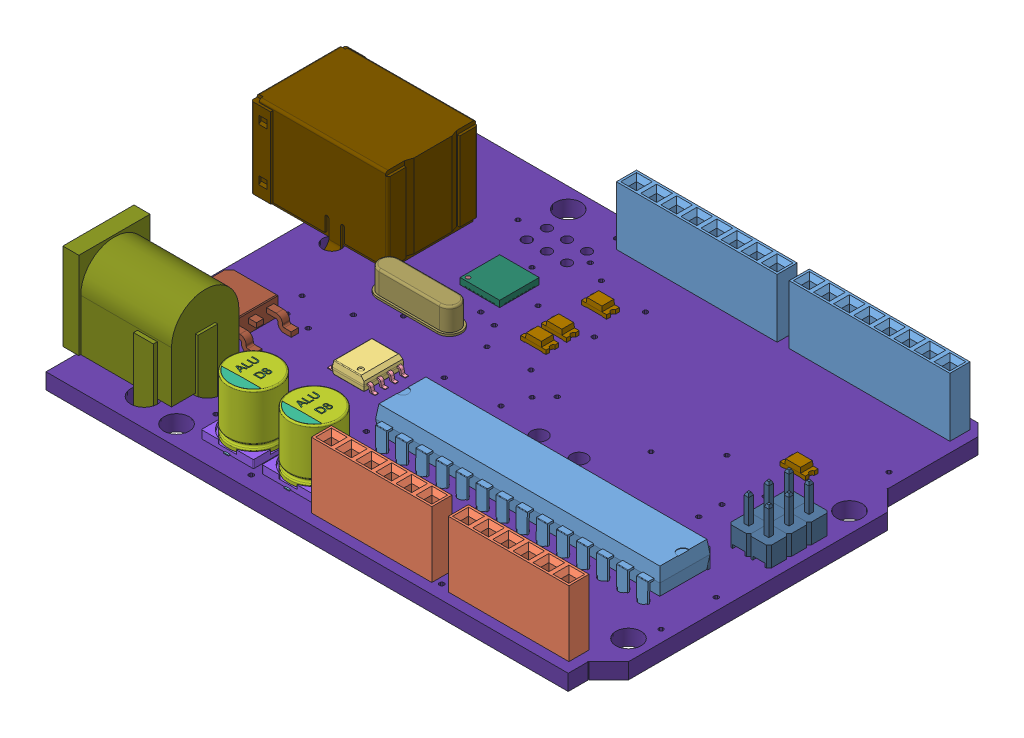
SolidWorks assembly ArduinoUno, configuration Predeterminado. Lengths in mm.
Overall size (75.71 19 55.26).
37 component instances, 20 part files, 8 mates.
Components (placement in the parent):
- Final-1: Final [Predeterminado] at (-36.0382 -5.851 101.423) size (74.75 15.48 53.34)
  - Stackable Female Pin Header_Default-1: Stackable Female Pin Header_Default [Predeterminado] at (23.9415 1.1201 -50.7298) size (20.32 8.3 2.54)
  - Stackable Female Pin Header_6 Way-1: Stackable Female Pin Header_6 Way [Predeterminado] at (33.5006 2 -2.5872) size (15.24 8.3 2.54)
  - User Library-SOIC-8_Default-1: User Library-SOIC-8_Default [Predeterminado] at (20.4108 1.85 -20.3024) x (0 0 -1) z (1 0 0) size (5 1.75 6.01)
    - User Library-SOIC-8_SOIC-8_Body_1_Default-1: User Library-SOIC-8_SOIC-8_Body_1_Default [Predeterminado] at origin size (5 1.6 4)
    - User Library-SOIC-8_SOIC-8_Pins_1_Default-1: User Library-SOIC-8_SOIC-8_Pins_1_Default [Predeterminado] at origin size (4.23 0.99 6.01)
  - User Library-ALU-D8_Default-1: User Library-ALU-D8_Default [Predeterminado] at (28.1214 1.8 -5.7935) x (0 0 -1) z (0 1 0) size (7 6.6 7.7)
    - User Library-ALU-D8_Pins_1_Default-1: User Library-ALU-D8_Pins_1_Default [Predeterminado] at origin size (7 0.65 0.4)
    - User Library-ALU-D8_Beschriftung_1_Default-1: User Library-ALU-D8_Beschriftung_1_Default [Predeterminado] at origin size (4.35 4.98 0.11)
    - User Library-ALU-D8_K_X_F6rper_1_Default-1: User Library-ALU-D8_K_X_F6rper_1_Default [Predeterminado] at origin size (6.3 6.3 7)
    - User Library-ALU-D8_Fuss_1_Default-1: User Library-ALU-D8_Fuss_1_Default [Predeterminado] at origin size (6.6 6.6 1)
  - User Library-ALU-D8_Default-2: User Library-ALU-D8_Default [Predeterminado] at (20.4464 1.8 -5.7935) x (0 0 -1) z (0 1 0) size (7 6.6 7.7)
    - User Library-ALU-D8_Pins_1_Default-1: User Library-ALU-D8_Pins_1_Default [Predeterminado] at origin size (7 0.65 0.4)
    - User Library-ALU-D8_Beschriftung_1_Default-1: User Library-ALU-D8_Beschriftung_1_Default [Predeterminado] at origin size (4.35 4.98 0.11)
    - User Library-ALU-D8_K_X_F6rper_1_Default-1: User Library-ALU-D8_K_X_F6rper_1_Default [Predeterminado] at origin size (6.3 6.3 7)
    - User Library-ALU-D8_Fuss_1_Default-1: User Library-ALU-D8_Fuss_1_Default [Predeterminado] at origin size (6.6 6.6 1)
  - Stackable Female Pin Header_Default-2: Stackable Female Pin Header_Default [Predeterminado] at (45.7158 1.1368 -50.806) size (20.32 8.3 2.54)
  - LED 1206_Default-1: LED 1206_Default [Predeterminado] at (28.1068 2 -36.9237) x (0 0 -1) z (1 0 0) size (1.6 1.1 3.2)
  - LED 1206_Default-2: LED 1206_Default [Predeterminado] at (58.3346 2 -36.8813) x (0 0 -1) z (1 0 0) size (1.6 1.1 3.2)
  - Header Vertical 2.54mm Pitch2_Header 6 Way-1: Header Vertical 2.54mm Pitch2_Header 6 Way [Predeterminado] at (62.2731 2 -29.1415) size (5.08 8.88 7.62)
  - SO 369A_Standard-1: SO 369A_Standard [Predeterminado] at (5.5398 2 -17.4191) x (0 0 -1) z (0 1 0) size (6.6 10.1 2.4)
  - Stackable Female Pin Header_6 Way-2: Stackable Female Pin Header_6 Way [Predeterminado] at (50.8347 2 -2.5872) size (15.24 8.3 2.54)
  - XTAL Small_Default-1: XTAL Small_Default [Predeterminado] at (14.2222 2 -30.4346) x (1 0 0) z (0 1 0) size (10.67 3.05 5.63)
  - LED 1206_Default-3: LED 1206_Default [Predeterminado] at (28.1068 2 -41.994) x (0 0 -1) z (1 0 0) size (1.6 1.1 3.2)
  - User Library-QFN32 (FTDI)_Default-1: User Library-QFN32 (FTDI)_Default [Predeterminado] at (19.2089 2.05 -38.1588) x (-1 0 0) z (0 1 0) size (5 5 0.81)
    - User Library-QFN32 (FTDI)_Beschriftung_1_Default-1: User Library-QFN32 (FTDI)_Beschriftung_1_Default [Predeterminado] at origin size (0.51 0.51 0.05)
    - User Library-QFN32 (FTDI)_Anschl_X_FCsse_1_Default-1: User Library-QFN32 (FTDI)_Anschl_X_FCsse_1_Default [Predeterminado] x (0 -1 0) z (0 0 1) size (3.86 0.12 0.12)
    - User Library-QFN32 (FTDI)_K_X_F6rper_1_Default-1: User Library-QFN32 (FTDI)_K_X_F6rper_1_Default [Predeterminado] at origin size (5 5 0.8)
  - User Library-dc range - dc connector[4840_2201]_Default-1: User Library-dc range - dc connector[4840_2201]_Default [Predeterminado] at (11.794 2 -12.8354) x (0 0 1) z (-1 0 0) size (9.51 14.5 13.83)
  - PCB_Final_Default-1: PCB_Final_Default [Predeterminado] at origin size (68.58 2 53.34)
  - LED 1206_Default-4: LED 1206_Default [Predeterminado] at (28.142 2 -34.2868) x (0 0 -1) z (1 0 0) size (1.6 1.1 3.2)
  - User Library-67068-0000-molex_Default-1: User Library-67068-0000-molex_Default [Predeterminado] at (-6.1546 2 -38.0545) x (0.002421 0 0.999997) z (-0.999997 0 0.002421) size (15.13 15.48 17)
  - IC DIP 28_Default-1: IC DIP 28_Default [Predeterminado] at (51.4233 4.3498 -16.4837) x (0 0.005002 0.999987) z (-1 0 0) size (7.87 6.22 35.94)
- separador-1: separador [Predeterminado] at (-22.0682 -11.851 98.883) x (1 0 0) z (0 1 0) size (7 7 6)
- separador-2: separador [Predeterminado] at (30.0018 -11.851 93.803) x (1 0 0) z (0 1 0) size (7 7 6)
- separador-3: separador [Predeterminado] at (30.0018 -11.851 65.863) x (1 0 0) z (0 1 0) size (7 7 6)
- separador-4: separador [Predeterminado] at (-20.7982 -11.851 50.623) x (1 0 0) z (0 1 0) size (7 7 6)
Mates (geometry in assembly coordinates):
- Coincident58: coincident: plane of Final-1/PCB_Final_Default-1 through (-69.6226 -5.851 74.7347) normal (0 -1 0); plane of separador-1 through (-22.0682 -5.851 98.883) normal (0 1 0)
- Concentric18: concentric: circle of Final-1/PCB_Final_Default-1; circle of separador-1
- Coincident60: coincident: plane of Final-1/PCB_Final_Default-1 through (-69.6226 -5.851 74.7347) normal (0 -1 0); plane of separador-2 through (30.0018 -5.851 93.803) normal (0 1 0)
- Concentric19: concentric: circle of Final-1/PCB_Final_Default-1; circle of separador-2
- Coincident61: coincident: plane of Final-1/PCB_Final_Default-1 through (-69.6226 -5.851 74.7347) normal (0 -1 0); plane of separador-3 through (30.0018 -5.851 65.863) normal (0 1 0)
- Concentric21: concentric: circle of Final-1/PCB_Final_Default-1; circle of separador-3
- Coincident59: coincident: plane of Final-1/PCB_Final_Default-1 through (-69.6226 -5.851 74.7347) normal (0 -1 0); plane of separador-4 through (-20.7982 -5.851 50.623) normal (0 1 0)
- Concentric20: concentric: circle of Final-1/PCB_Final_Default-1; circle of separador-4
